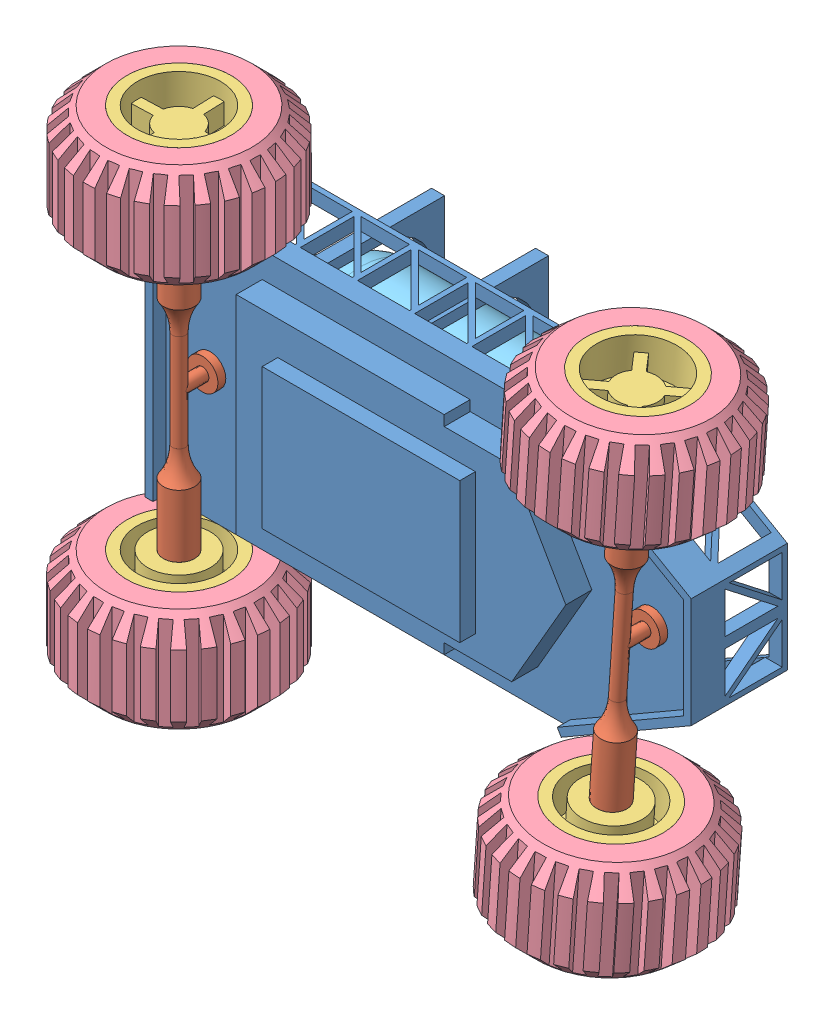
SolidWorks assembly UGV, configuration Default. Lengths in mm.
Overall size (138.68 97.3 64.88).
16 component instances, 5 part files, 16 mates.
Components (placement in the parent):
- Body-1: Body [Default] at (19.1987 58.6484 95.6834) size (105 50 37)
- Steering-1: Steering [Default] at (76.0767 85.583 102.6834) x (-0.997578 0.069557 0) z (-0.069557 -0.997578 0) size (6 10 54)
- Tyre Assembly-1: Tyre Assembly [Default] at (-10.8013 22.0001 102.6834) x (0.817348 0 0.576144) z (0 1 0) size (36 35.97 20)
  - Part6-1: Part6 [Default] at origin size (20 20 20)
  - Tyre-1: Tyre [Default] at (0 0 -5.3518) size (36 35.97 20)
- Steering-2: Steering [Default] at (-10.8013 85.6484 102.6834) x (-1 0 0) z (0 -1 0) size (6 10 54)
- Tyre Assembly-2: Tyre Assembly [Default] at (-10.8013 95.2966 102.6834) x (-0.999377 0 0.035286) z (0 -1 0) size (36 35.97 20)
  - Part6-1: Part6 [Default] at origin size (20 20 20)
  - Tyre-1: Tyre [Default] at (0 0 -5.3518) size (36 35.97 20)
- Tyre Assembly-3: Tyre Assembly [Default] at (71.6496 22.0889 102.6834) x (0.777053 -0.054181 -0.627099) z (0.069557 0.997578 0) size (36 35.97 20)
  - Part6-1: Part6 [Default] at origin size (20 20 20)
  - Tyre-1: Tyre [Default] at (0 0 -5.3518) size (36 35.97 20)
- Tyre Assembly-4: Tyre Assembly [Default] at (76.7478 95.2079 102.6834) x (-0.755348 0.052667 0.653204) z (-0.069557 -0.997578 0) size (36 35.97 20)
  - Part6-1: Part6 [Default] at origin size (20 20 20)
  - Tyre-1: Tyre [Default] at (0 0 -5.3518) size (36 35.97 20)
- Object-1: Object [Default] at (38.2238 58.6484 79.3173) x (0 -0.032521 0.999471) z (-1 0 0) size (31.31 29.4 65)
Mates (geometry in assembly coordinates):
- Coincident1: coincident anti-aligned: plane of Body-1 through (19.1987 58.6484 95.6834) normal (0 0 1); plane of Steering-1 through (74.1987 58.6484 95.6834) normal (0 0 -1)
- Concentric1: concentric anti-aligned: cylinder of Body-1 through (74.1987 58.6484 96.6834) axis (0 0 -1) radius 3; cylinder of Steering-1 through (74.1987 58.6484 95.6834) axis (0 0 1) radius 3
- Coincident2: coincident anti-aligned: plane of Body-1 through (19.1987 58.6484 95.6834) normal (0 0 1); plane of Steering-2 through (-10.8013 58.6484 95.6834) normal (0 0 -1)
- Concentric2: concentric anti-aligned: cylinder of Body-1 through (-10.8013 58.6484 96.6834) axis (0 0 -1) radius 3; cylinder of Steering-2 through (-10.8013 58.6484 95.6834) axis (0 0 1) radius 3
- Parallel1: parallel aligned: plane of Body-1 through (-20.8013 83.6484 93.6834) normal (0 1 0); plane of Steering-2 through (-10.8013 85.6484 102.6834) normal (0 1 0)
- Coincident4: coincident anti-aligned: plane of Tyre Assembly-1/Part6-1 through (-10.8013 31.6484 102.6834) normal (0 1 0); plane of Steering-2 through (-10.8013 31.6484 102.6834) normal (0 -1 0)
- Concentric3: concentric anti-aligned: cylinder of Tyre Assembly-1/Part6-1 through (-10.8013 36.7429 102.6834) axis (0 1 0) radius 6; cylinder of Steering-2 through (-10.8013 43.6484 102.6834) axis (0 -1 0) radius 3
- Coincident5: coincident anti-aligned: plane of Steering-1 through (72.3207 31.7138 102.6834) normal (-0.069557 -0.997578 0); plane of Tyre Assembly-3/Part6-1 through (72.3207 31.7138 102.6834) normal (0.069557 0.997578 0)
- Concentric4: concentric anti-aligned: cylinder of Steering-1 through (73.1554 43.6847 102.6834) axis (-0.069557 -0.997578 0) radius 3; cylinder of Tyre Assembly-3/Part6-1 through (72.675 36.796 102.6834) axis (0.069557 0.997578 0) radius 6
- Coincident6: coincident anti-aligned: plane of Steering-1 through (76.0767 85.583 102.6834) normal (0.069557 0.997578 0); plane of Tyre Assembly-4/Part6-1 through (76.0767 85.583 102.6834) normal (-0.069557 -0.997578 0)
- Concentric5: concentric anti-aligned: cylinder of Steering-1 through (75.2421 73.612 102.6834) axis (0.069557 0.997578 0) radius 3; cylinder of Tyre Assembly-4/Part6-1 through (75.7224 80.5008 102.6834) axis (-0.069557 -0.997578 0) radius 6
- Coincident7: coincident anti-aligned: plane of Steering-2 through (-10.8013 85.6484 102.6834) normal (0 1 0); plane of Tyre Assembly-2/Part6-1 through (-10.8013 85.6484 102.6834) normal (0 -1 0)
- Concentric6: concentric anti-aligned: cylinder of Steering-2 through (-10.8013 73.6484 102.6834) axis (0 1 0) radius 3; cylinder of Tyre Assembly-2/Part6-1 through (-10.8013 80.5538 102.6834) axis (0 -1 0) radius 6
- Coincident8: coincident: line of Body-1 through (25.2782 69.1484 69.6834) axis (-1 0 0); cylinder of Object-1 through (-1.7762 58.6484 79.3173) axis (1 0 0) radius 14.25
- Coincident9: coincident: line of Body-1 through (25.2782 48.1484 69.6834) axis (-1 0 0); cylinder of Object-1 through (-1.7762 58.6484 79.3173) axis (1 0 0) radius 14.25
- Tangent1: tangent anti-aligned: plane of Body-1 through (45.1013 36.1484 80.6834) normal (-1 0 0); torus of Object-1
